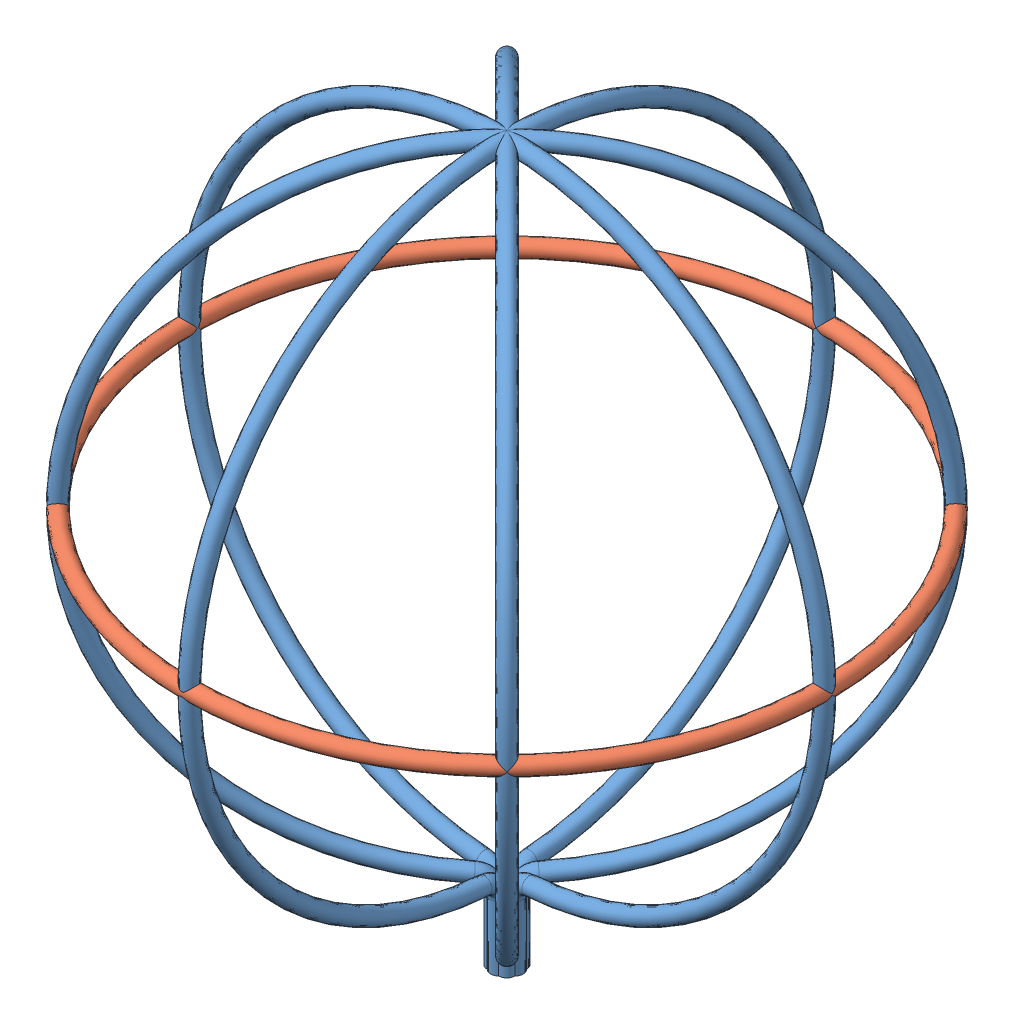
SolidWorks assembly Cathode, configuration Default. Lengths in mm.
Overall size (52.1 57.79 52.1).
5 component instances, 2 part files, 11 mates.
Components (placement in the parent):
- Cathode Longitude-1: Cathode Longitude [Default] at (23.1416 39.3287 39.2327) size (52.1 57.79 1.3)
- Cathode Longitude-2: Cathode Longitude [Default] at (23.1416 39.3287 39.2327) x (0 0 1) z (-1 0 0) size (52.1 57.79 1.3)
- Cathode Longitude-3: Cathode Longitude [Default] at (23.1416 39.3287 39.2327) x (0.707107 0 0.707107) z (-0.707107 0 0.707107) size (52.1 57.79 1.3)
- Cathode Longitude-4: Cathode Longitude [Default] at (23.1416 39.3287 39.2327) x (-0.707107 0 0.707107) z (-0.707107 0 -0.707107) size (52.1 57.79 1.3)
- Cathode Equator-1: Cathode Equator [Default] at (23.1416 39.3287 39.2327) size (52.1 1.3 52.1)
Mates (geometry in assembly coordinates):
- Coincident1: coincident aligned: line of Cathode Longitude-1 through (23.1416 4.6978 39.2327) axis (0 1 0); line of Cathode Longitude-2 through (23.1416 4.6978 39.2327) axis (0 1 0)
- Coincident2: coincident aligned: line of Cathode Longitude-1 through (23.1416 4.6978 39.2327) axis (0 1 0); line of Cathode Longitude-4 through (23.1416 4.6978 39.2327) axis (0 1 0)
- Coincident3: coincident aligned: line of Cathode Longitude-1 through (23.1416 4.6978 39.2327) axis (0 1 0); line of Cathode Longitude-3 through (23.1416 4.6978 39.2327) axis (0 1 0)
- Coincident4: coincident aligned: plane of Cathode Longitude-1 through (22.4812 7.5873 39.2327) normal (0 -1 0); plane of Cathode Longitude-4 through (23.6086 7.5873 38.7657) normal (0 -1 0)
- Coincident5: coincident aligned: plane of Cathode Longitude-1 through (22.4812 7.5873 39.2327) normal (0 -1 0); plane of Cathode Longitude-2 through (23.1416 7.5873 38.5723) normal (0 -1 0)
- Coincident6: coincident aligned: plane of Cathode Longitude-1 through (22.4812 7.5873 39.2327) normal (0 -1 0); plane of Cathode Longitude-3 through (22.6747 7.5873 38.7657) normal (0 -1 0)
- Perpendicular1: perpendicular: plane of Cathode Longitude-1 through (23.1416 39.3287 39.2327) normal (0 0 1); plane of Cathode Longitude-2 through (23.1416 39.3287 39.2327) normal (-1 0 0)
- Angle1: planar angle = 0.785398 rad aligned: plane of Cathode Longitude-1 through (23.1416 39.3287 39.2327) normal (0 0 1); plane of Cathode Longitude-3 through (23.1416 39.3287 39.2327) normal (-0.707107 0 0.707107)
- Angle2: planar angle = 2.356194 rad aligned: plane of Cathode Longitude-1 through (23.1416 39.3287 39.2327) normal (0 0 1); plane of Cathode Longitude-4 through (23.1416 39.3287 39.2327) normal (-0.707107 0 -0.707107)
- Coincident10: coincident aligned: plane of Cathode Longitude-1 through (23.1416 39.3287 39.2327) normal (0 1 0); plane of Cathode Equator-1 through (23.1416 39.3287 39.2327) normal (0 1 0)
- Coincident11: coincident aligned: line of Cathode Longitude-1 through (23.1416 4.6978 39.2327) axis (0 1 0); axis of Cathode Equator-1 through (23.1416 24.5916 39.2327) axis (0 1 0)
